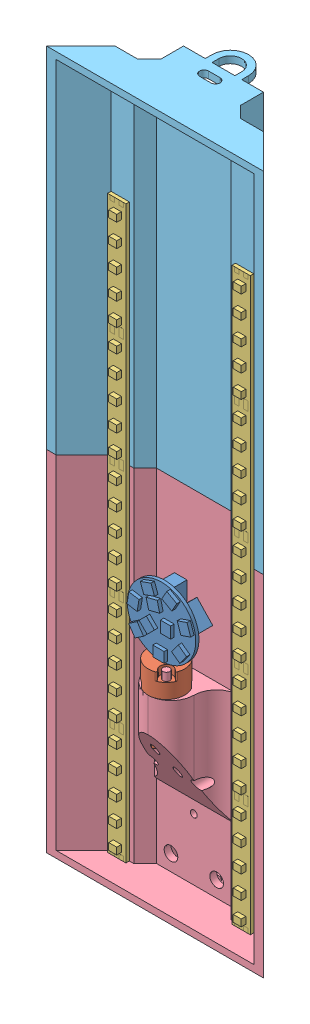
SolidWorks assembly Center-Decke, configuration Standard. Lengths in mm.
Overall size (95 306 47.31).
6 component instances, 5 part files, 15 mates.
Components (placement in the parent):
- G4 LED-1: G4 LED [Standard] at (-69.3938 71.9428 102.9201) x (-1 0 0) z (0 1 0) size (30 9.9 34.79)
- G4 Sockel-1: G4 Sockel [Standard] at (-69.3938 46.9428 102.1701) x (0.707107 0 0.707107) z (0 1 0) size (16 16 33.5)
- LED-Bar-1: LED-Bar [Standard] at (-38.1365 214.9428 95.1701) x (0 1 0) z (1 0 0) size (250 3.5 8)
- LED-Bar-2: LED-Bar [Standard] at (-92.6512 214.9428 95.1701) x (0 1 0) z (1 0 0) size (250 3.5 8)
- Center-Decke-Gehäuse-Left-1: Center-Decke-Gehäuse-Left [Standard] at (-69.3938 -38.0572 77.1701) size (95 157.8 44)
- Center-Decke-Gehäuse-Right-1: Center-Decke-Gehäuse-Right [Standard] at (-69.3938 267.9428 77.1701) x (-1 0 0) z (0 0 1) size (95 153 41)
Mates (geometry in assembly coordinates):
- Deckungsgleich1: coincident anti-aligned: plane of LED-Bar-1 through (-38.1365 214.9428 95.1701) normal (0 0 -1); plane of Center-Decke-Gehäuse-Left-1 through (-48.1365 114.9428 95.1701) normal (0 0 1)
- Deckungsgleich2: coincident anti-aligned: plane of LED-Bar-2 through (-92.6512 214.9428 95.1701) normal (0 0 -1); plane of Center-Decke-Gehäuse-Left-1 through (-90.6512 114.9428 95.1701) normal (0 0 1)
- Deckungsgleich3: coincident anti-aligned: plane of LED-Bar-2 through (-92.6512 -35.0572 96.6701) normal (0 -1 0); plane of Center-Decke-Gehäuse-Left-1 through (-69.3938 -35.0572 77.1701) normal (0 1 0)
- Deckungsgleich4: coincident anti-aligned: plane of LED-Bar-1 through (-38.1365 -35.0572 96.6701) normal (0 -1 0); plane of Center-Decke-Gehäuse-Left-1 through (-69.3938 -35.0572 77.1701) normal (0 1 0)
- Deckungsgleich5: coincident anti-aligned: line of LED-Bar-1 through (-38.1365 -35.0572 95.1701) axis (0 1 0); line of Center-Decke-Gehäuse-Left-1 through (-38.1365 114.9428 95.1701) axis (0 -1 0)
- Deckungsgleich6: coincident aligned: line of LED-Bar-2 through (-100.6512 214.9428 95.1701) axis (0 -1 0); line of Center-Decke-Gehäuse-Left-1 through (-100.6512 114.9428 95.1701) axis (0 -1 0)
- Deckungsgleich7: coincident anti-aligned: plane of G4 Sockel-1 through (-69.3938 46.9428 102.1701) normal (0 -1 0); plane of Center-Decke-Gehäuse-Left-1 through (-79.3938 46.9428 110.1701) normal (0 1 0)
- Konzentrisch1: concentric anti-aligned: cylinder of G4 Sockel-1 through (-73.6365 46.9428 97.9274) axis (0 1 0) radius 1.5; cylinder of Center-Decke-Gehäuse-Left-1 through (-73.6365 56.9428 97.9274) axis (0 -1 0) radius 1.5
- Konzentrisch2: concentric anti-aligned: cylinder of G4 Sockel-1 through (-65.1512 46.9428 106.4127) axis (0 1 0) radius 1.5; cylinder of Center-Decke-Gehäuse-Left-1 through (-65.1512 56.9428 106.4127) axis (0 -1 0) radius 1.5
- Konzentrisch3: concentric anti-aligned: cylinder of G4 Sockel-1 through (-66.8938 46.9428 102.1701) axis (0 1 0) radius 0.75; cylinder of G4 LED-1 through (-66.8938 59.6577 102.1701) axis (0 -1 0) radius 0.75
- Konzentrisch4: concentric anti-aligned: cylinder of G4 LED-1 through (-71.8938 59.6577 102.1701) axis (0 -1 0) radius 0.75; cylinder of G4 Sockel-1 through (-71.8938 46.9428 102.1701) axis (0 1 0) radius 0.75
- Tangential2: tangent anti-aligned: cylinder of G4 LED-1 through (-69.3938 71.9428 104.3201) axis (0 0 -1) radius 15; plane of G4 Sockel-1 through (-69.3938 56.9428 102.1701) normal (0 1 0)
- Deckungsgleich8: coincident: plane of Center-Decke-Gehäuse-Left-1 through (-69.3938 114.9428 77.1701) normal (0 1 0); plane of Center-Decke-Gehäuse-Right-1 through (-69.3938 114.9428 77.1701) normal (0 -1 0)
- Deckungsgleich9: coincident: line of Center-Decke-Gehäuse-Left-1 through (-101.8938 114.9428 92.1701) axis (-0.707107 0 0.707107); line of Center-Decke-Gehäuse-Right-1 through (-107.7015 114.9428 97.9777) axis (0.707107 0 -0.707107)
- Deckungsgleich10: coincident anti-aligned: line of Center-Decke-Gehäuse-Left-1 through (-30.9448 114.9428 98.1191) axis (-0.707107 0 -0.707107); line of Center-Decke-Gehäuse-Right-1 through (-36.8938 114.9428 92.1701) axis (0.707107 0 0.707107)
